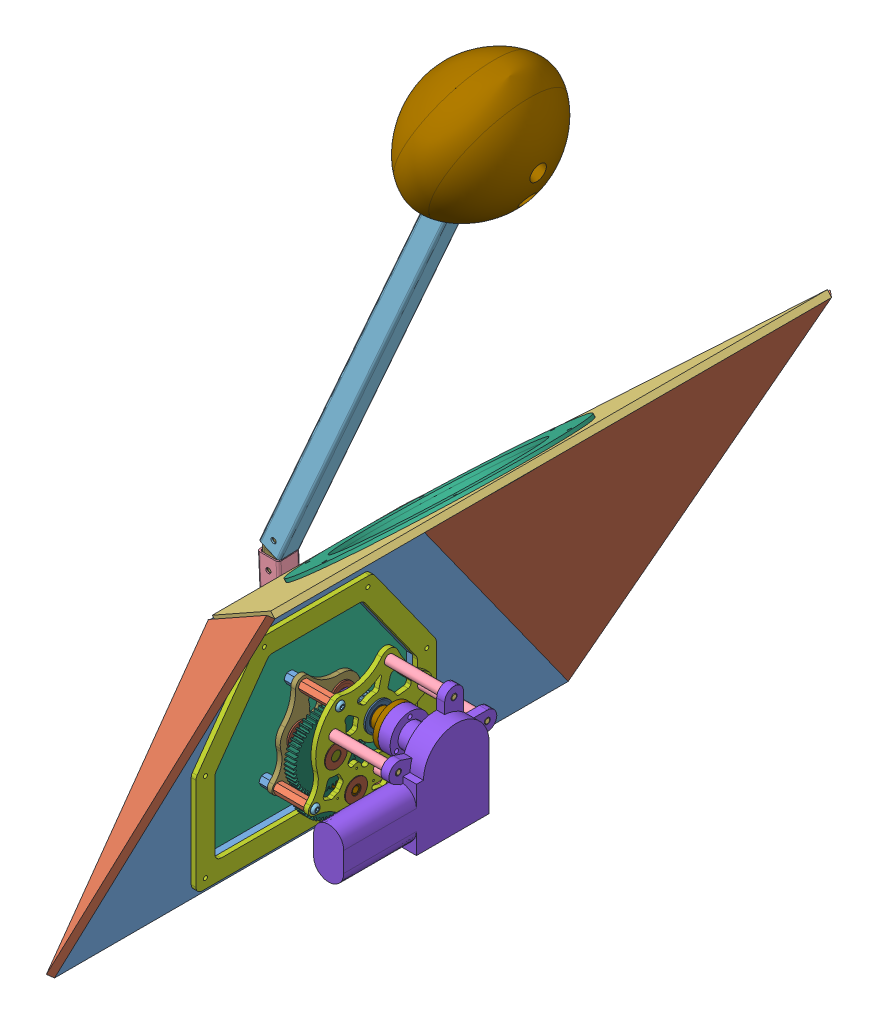
SolidWorks assembly Movable_Ballast, configuration Default. Lengths in mm.
Overall size (379.88 814.25 565.55).
62 component instances, 31 part files, 41 mates.
Components (placement in the parent):
- AngledBallast_DeckFront-1: AngledBallast_DeckFront [Default] at (17.6155 154.4397 181.7513) size (6.35 227.24 515.62)
- AngledBallast_DeckSides-1: AngledBallast_DeckSides [Default] at (23.9655 154.4397 439.5613) x (-0.750947 0.384211 0.537086) z (-0.47901 -0.876778 -0.042532) size (6.35 202.67 506.73)
- AngledBallast_DeckBack-1: AngledBallast_DeckBack [Default] at (262.5116 603.5077 -97.6487) x (0.666573 -0.74544 0) z (0 0 -1) size (6.35 325.69 558.8)
- AngledBallast_DeckSides-2: AngledBallast_DeckSides [Default] at (19.197 156.8794 -79.4692) x (0.750947 -0.384211 0.537086) z (-0.47901 -0.876778 0.042532) size (6.35 202.67 506.73)
- Ballast_Arm_Link1-1: Ballast_Arm_Link1 [Default] at (-1.1805 227.4494 182.4482) x (0 0.0439 -0.999036) z (0 0.999036 0.0439) size (21.59 21.59 161.93)
- Ballast_Arm_Link2-1: Ballast_Arm_Link2 [Default] at (212.1678 849.4759 209.7816) x (0 -0.0439 0.999036) z (-0.422618 -0.905434 -0.039787) size (21.97 21.97 501.65)
- 8inchHatch-2: 8inchHatch [Default] at (159.9893 499.0544 181.7513) x (0.74544 0.666573 0) z (0 0 1) size (248.92 12.7 248.92)
- LoweredMovableBallast-1: LoweredMovableBallast [AlternativeShaft] at (27.1405 211.5897 181.7513) x (0 -1 0) z (0 0 1) size (175.94 151.42 194.47)
  - Lowered_Ballast_Motor_Mount-1: Lowered_Ballast_Motor_Mount [Default] at (-131.0617 41.275 -47.2491) x (0 -1 0) z (-0.891007 0 0.45399) size (4.86 136.94 127.69)
  - Ballast_Motor_Mock-1: Ballast_Motor_Mock [Default] at (-52.6913 119.925 -55.3661) x (0 -1 0) z (0 0 1) size (58.5 115.03 167.12)
  - Ballast_Motor_Hub-1: Ballast_Motor_Hub [Default] at (-52.6913 61.425 -22.3661) x (-0.866025 0 -0.5) z (0 -1 0) size (40 40 17.78)
  - Hex_1_2in_Bearing_217-3875-STEP-20140818-1: Hex_1_2in_Bearing_217-3875-STEP-20140818 [Default] at (-52.6913 42.8625 -22.3661) x (-0.866025 0 -0.5) z (-0.5 0 0.866025) size (31.12 7.94 31.12)
  - 217-2733.20121205-1: 217-2733.20121205 [Default] at (-39.6731 34.925 20.2145) x (0 1 0) z (0.924225 0 0.381849) size (7.11 24.61 24.61)
  - 217-2733.20121205-2: 217-2733.20121205 [Default] at (0 34.925 0) x (0 1 0) z (-0.995143 0 0.098436) size (7.11 24.61 24.61)
  - Movable_Ballast_GearboxTopPlate-1: Movable_Ballast_GearboxTopPlate [Default] at (-131.0617 9.525 -47.2491) x (0 -1 0) z (-0.891007 0 0.45399) size (4.76 104.01 127.69)
  - 217-2733.20121205-3: 217-2733.20121205 [Default] at (-39.6731 6.35 20.2145) x (0 -1 0) z (0 0 1) size (7.11 24.61 24.61)
  - 217-2733.20121205-4: 217-2733.20121205 [Default] at (-52.6913 6.35 -22.3661) x (0 -1 0) z (0 0 1) size (7.11 24.61 24.61)
  - 217-2731.20121205-1: 217-2731.20121205 [Default] at (0 -1.5875 0) x (-0.381849 0 0.924225) z (-0.924225 0 -0.381849) size (31.12 7.94 31.12)
  - 217-3209-STEP-1: 217-3209-STEP [Default] at (-39.6731 16.0004 20.2145) x (0.901904 0 0.431937) z (0 1 0) size (25.77 25.98 12.65)
  - 217-3209-STEP-2: 217-3209-STEP [Default] at (-52.6913 29.895 -22.3661) x (-0.5 0 0.866025) z (0 -1 0) size (25.77 25.98 12.65)
  - 217-5473-STEP-1: 217-5473-STEP [Default] at (0 14.7304 0) x (0.887141 0 0.461499) z (0 -1 0) size (69.25 69.25 12.6)
  - 217-5473-STEP-2: 217-5473-STEP [Default] at (-39.6731 28.625 20.2145) x (-0.901904 0 -0.431937) z (0 -1 0) size (69.25 69.25 12.6)
  - MoveableBallast_IntermediateShaft-1: MoveableBallast_IntermediateShaft [Default] at (-39.6731 20.7645 20.2145) x (-0.82502 0 0.565103) z (0.565103 0 0.82502) size (12.7 41.27 14.66)
  - MoveableBallast_InputShaft-1: MoveableBallast_InputShaft [Default] at (-52.6913 61.425 -22.3661) x (0.5 0 0.866025) z (0.866025 0 -0.5) size (12.7 60.96 14.66)
  - MoveableBallast_OutputShaft-1: MoveableBallast_OutputShaft [AlternativeShaft] at (0 34.925 0) x (0.0439 0 0.999036) z (0.999036 0 -0.0439) size (12.7 72.77 14.66)
  - 91075A171_18-8 SS MALE-FEM THRDED HEX STANDOFF-5: 91075A171_18-8 SS MALE-FEM THRDED HEX STANDOFF [91075A171] at (-4.0577 0 41.0751) x (0 1 0) z (-0.999527 0 0.030764) size (19.59 11 9.53)
  - 91075A171_18-8 SS MALE-FEM THRDED HEX STANDOFF-6: 91075A171_18-8 SS MALE-FEM THRDED HEX STANDOFF [91075A171] at (-80.7194 0 15.875) x (0 1 0) z (0.485103 0 0.874457) size (19.59 11 9.53)
  - 91075A171_18-8 SS MALE-FEM THRDED HEX STANDOFF-3: 91075A171_18-8 SS MALE-FEM THRDED HEX STANDOFF [91075A171] at (19.05 0 -38.1) x (0 1 0) z (-0.636236 0 0.771494) size (19.59 11 9.53)
  - 91075A171_18-8 SS MALE-FEM THRDED HEX STANDOFF-4: 91075A171_18-8 SS MALE-FEM THRDED HEX STANDOFF [91075A171] at (-34.925 0 -38.1) x (0 1 0) z (0.444729 0 -0.895665) size (19.59 11 9.53)
  - 91780A304_ALUM FEM THRDED HEX STANDOFF-6: 91780A304_ALUM FEM THRDED HEX STANDOFF [91780A304] at (-4.0577 20.6375 41.0751) x (-0.985591 0 -0.169146) z (0 1 0) size (9.53 11 32.37)
  - 91780A304_ALUM FEM THRDED HEX STANDOFF-8: 91780A304_ALUM FEM THRDED HEX STANDOFF [91780A304] at (-34.925 20.6375 -38.1) x (1 0 0) z (0 -1 0) size (9.53 11 32.37)
  - 91780A304_ALUM FEM THRDED HEX STANDOFF-9: 91780A304_ALUM FEM THRDED HEX STANDOFF [91780A304] at (-80.7194 20.6375 15.875) x (1 0 0) z (0 1 0) size (9.53 11 32.37)
  - 91780A304_ALUM FEM THRDED HEX STANDOFF-10: 91780A304_ALUM FEM THRDED HEX STANDOFF [91780A304] at (19.05 20.6375 -38.1) x (0.996824 0 -0.079633) z (0 -1 0) size (9.53 11 32.37)
  - 92125A258_TYPE 18-8 SS FLAT-HEAD SOCKET CAP SCREW-1: 92125A258_TYPE 18-8 SS FLAT-HEAD SOCKET CAP SCREW [92125A258] at (-96.1913 36.5125 -33.6661) x (1 0 0) z (0 -1 0) size (12 12 70.91)
  - 92125A258_TYPE 18-8 SS FLAT-HEAD SOCKET CAP SCREW-2: 92125A258_TYPE 18-8 SS FLAT-HEAD SOCKET CAP SCREW [92125A258] at (-58.6913 36.5125 -66.9661) x (1 0 0) z (0 -1 0) size (12 12 70.91)
  - 92125A258_TYPE 18-8 SS FLAT-HEAD SOCKET CAP SCREW-3: 92125A258_TYPE 18-8 SS FLAT-HEAD SOCKET CAP SCREW [92125A258] at (-58.6913 36.5125 22.2339) x (-0.551717 0 0.834031) z (0 -1 0) size (12 12 70.91)
  - 92125A258_TYPE 18-8 SS FLAT-HEAD SOCKET CAP SCREW-4: 92125A258_TYPE 18-8 SS FLAT-HEAD SOCKET CAP SCREW [92125A258] at (-7.6913 36.5125 -22.3661) x (1 0 0) z (0 -1 0) size (12 12 70.91)
  - MoveableBallast_MotorSpacer_9038K24_Stock-1: MoveableBallast_MotorSpacer_9038K24_Stock [Default] at (-58.6913 41.275 -66.9661) x (-0.794722 0 -0.606973) z (0.606973 0 -0.794722) size (9.53 57.15 9.53)
  - MoveableBallast_MotorSpacer_9038K24_Stock-2: MoveableBallast_MotorSpacer_9038K24_Stock [Default] at (-7.6913 41.275 -22.3661) x (0.166881 0 0.985977) z (-0.985977 0 0.166881) size (9.53 57.15 9.53)
  - MoveableBallast_MotorSpacer_9038K24_Stock-3: MoveableBallast_MotorSpacer_9038K24_Stock [Default] at (-96.1913 41.275 -33.6661) x (0.202474 0 0.979288) z (-0.979288 0 0.202474) size (9.53 57.15 9.53)
  - MoveableBallast_MotorSpacer_9038K24_Stock-4: MoveableBallast_MotorSpacer_9038K24_Stock [Default] at (-58.6913 41.275 22.2339) x (0.889131 0 0.457652) z (-0.457652 0 0.889131) size (9.53 57.15 9.53)
  - 92949A263_18-8 SS BUTTON-HEAD SOCKET CAP SCREW-1: 92949A263_18-8 SS BUTTON-HEAD SOCKET CAP SCREW [92949A263] at (-80.7194 43.8404 15.875) x (0.459564 0 -0.888145) z (0 1 0) size (9.17 9.17 12.55)
  - 92949A263_18-8 SS BUTTON-HEAD SOCKET CAP SCREW-2: 92949A263_18-8 SS BUTTON-HEAD SOCKET CAP SCREW [92949A263] at (-4.0577 43.8404 41.0751) x (1 0 0) z (0 1 0) size (9.17 9.17 12.55)
  - 92949A263_18-8 SS BUTTON-HEAD SOCKET CAP SCREW-3: 92949A263_18-8 SS BUTTON-HEAD SOCKET CAP SCREW [92949A263] at (19.05 43.8404 -38.1) x (1 0 0) z (0 1 0) size (9.17 9.17 12.55)
  - 92949A263_18-8 SS BUTTON-HEAD SOCKET CAP SCREW-4: 92949A263_18-8 SS BUTTON-HEAD SOCKET CAP SCREW [92949A263] at (-34.925 43.8404 -38.1) x (1 0 0) z (0 1 0) size (9.17 9.17 12.55)
- LoweredBallast_Deck_Mount-1: LoweredBallast_Deck_Mount [Default] at (23.9655 154.4397 181.7513) x (-1 0 0) z (0 0 -1) size (11.43 227.24 515.62)
- LoweredBallast_DeckMount_ClampPlate-1: LoweredBallast_DeckMount_ClampPlate [Default] at (17.6155 154.4397 181.7513) size (11.11 227.24 515.62)
- 92949A263_18-8 SS BUTTON-HEAD SOCKET CAP SCREW-1: 92949A263_18-8 SS BUTTON-HEAD SOCKET CAP SCREW [92949A263] at (9.9701 246.5147 143.6513) x (0 -0.883456 -0.468514) z (-1 0 0) size (9.17 9.17 12.55)
- 92949A263_18-8 SS BUTTON-HEAD SOCKET CAP SCREW-2: 92949A263_18-8 SS BUTTON-HEAD SOCKET CAP SCREW [92949A263] at (9.9701 192.5397 143.6513) x (0 0.924225 0.381849) z (-1 0 0) size (9.17 9.17 12.55)
- 92949A263_18-8 SS BUTTON-HEAD SOCKET CAP SCREW-3: 92949A263_18-8 SS BUTTON-HEAD SOCKET CAP SCREW [92949A263] at (9.9701 215.6473 222.8264) x (0 0.91527 -0.402841) z (-1 0 0) size (9.17 9.17 12.55)
- 92949A263_18-8 SS BUTTON-HEAD SOCKET CAP SCREW-4: 92949A263_18-8 SS BUTTON-HEAD SOCKET CAP SCREW [92949A263] at (9.9701 292.3091 197.6263) x (0 0 1) z (-1 0 0) size (9.17 9.17 12.55)
- 13125K830_CHEMICAL-RESISTANT SHAFT SEAL-1: 13125K830_CHEMICAL-RESISTANT SHAFT SEAL [13125K83] at (14.7199 211.5897 181.7513) x (1 0 0) z (0 -0.168673 0.985672) size (4.37 19.67 19.67)
- Ballast_Weight_Assembly-1: Ballast_Weight_Assembly [Default] at (222.9023 872.474 210.7922) x (-0.422618 -0.905434 -0.039787) z (0 0.0439 -0.999036) size (152.07 114.4 139.83)
  - Ballast_Weight-1: Ballast_Weight [Default] at origin size (152.07 114.4 139.83)
  - Ballast_Weight-2: Ballast_Weight [Ballast Weight Outside] at origin size (144.63 51.5 137.25)
  - Ballast_Weight-3: Ballast_Weight [Ballast Weight Outside] x (1 0 0) z (0 0 -1) size (144.63 51.5 137.25)
  - 92196A554_18-8 STAINLESS STEEL SOCKET HEAD CAP SCREW-1: 92196A554_18-8 STAINLESS STEEL SOCKET HEAD CAP SCREW [92196A554] at (12.7 41.275 0) x (1 0 0) z (0 1 0) size (9.53 9.53 83.33)
  - 92196A554_18-8 STAINLESS STEEL SOCKET HEAD CAP SCREW-2: 92196A554_18-8 STAINLESS STEEL SOCKET HEAD CAP SCREW [92196A554] at (-20.32 41.275 0) x (0.947644 0 -0.319328) z (0 1 0) size (9.53 9.53 83.33)
  - 92673A113_ASTM F594 TYPE 18-8 STAINLESS STEEL HEX NUT-2: 92673A113_ASTM F594 TYPE 18-8 STAINLESS STEEL HEX NUT [92673A113] at (-20.32 37.7031 0) x (1 0 0) z (0 1 0) size (11.11 12.83 7.14)
  - 92673A113_ASTM F594 TYPE 18-8 STAINLESS STEEL HEX NUT-3: 92673A113_ASTM F594 TYPE 18-8 STAINLESS STEEL HEX NUT [92673A113] at (12.7 37.7031 0) x (0.939231 0 0.343287) z (0 1 0) size (11.11 12.83 7.14)
- Ballast_Arm_Joint-1: Ballast_Arm_Joint [Default<As Machined>] at (-1.1805 392.3902 189.6961) x (0.21644 0.975355 0.04286) z (0.976296 -0.216231 -0.009502) size (59.92 19.06 25.24)
- AlternativeMBCoupler-1: AlternativeMBCoupler [Default] at (-1.1805 252.8249 183.5633) x (0 -0.0439 0.999036) z (0 -0.999036 -0.0439) size (19.05 19.05 50.8)
Mates (geometry in assembly coordinates):
- Coincident10: coincident aligned: line of AngledBallast_DeckFront-1 through (23.9655 381.681 277.0013) axis (0 -0.813319 0.581818); line of AngledBallast_DeckSides-1 through (23.9655 381.681 277.0013) axis (0 -0.813319 0.581818)
- Coincident11: coincident aligned: line of AngledBallast_DeckBack-1 through (266.7443 598.7742 461.1513) axis (-0.648895 -0.580243 -0.492193); line of AngledBallast_DeckSides-1 through (266.6944 598.7295 461.1134) axis (-0.648895 -0.580243 -0.492193)
- Coincident12: coincident anti-aligned: line of AngledBallast_DeckBack-1 through (23.9655 381.681 86.5013) axis (0.648895 0.580243 -0.492193); line of AngledBallast_DeckSides-2 through (266.6944 598.7295 -97.6108) axis (-0.648895 -0.580243 0.492193)
- Coincident13: coincident anti-aligned: line of AngledBallast_DeckFront-1 through (23.9655 154.4397 -76.0587) axis (0 0.813319 0.581818); line of AngledBallast_DeckSides-2 through (23.9655 381.681 86.5013) axis (0 -0.813319 -0.581818)
- Coincident30: coincident anti-aligned: line of AngledBallast_DeckFront-1 through (23.9655 381.681 86.5013) axis (0 0 1); line of AngledBallast_DeckBack-1 through (23.9655 381.681 277.0013) axis (0 0 -1)
- Concentric4: concentric aligned: circle of AngledBallast_DeckBack-1; circle of 8inchHatch-2
- Coincident58: coincident anti-aligned: plane of AngledBallast_DeckBack-1 through (262.5116 603.5077 -97.6487) normal (-0.666573 0.74544 0); plane of 8inchHatch-2 through (153.6401 506.1547 89.0413) normal (0.666573 -0.74544 0)
- Parallel2: parallel aligned: line of AngledBallast_DeckFront-1 through (17.6155 179.8397 283.3513) axis (0 0 -1); line of LoweredMovableBallast-1/Ballast_Motor_Mock-1 through (125.5655 202.281 199.3852) axis (0 0 -1)
- Concentric10: concentric anti-aligned: cylinder of LoweredMovableBallast-1/MoveableBallast_OutputShaft-1 through (-4.3555 211.5897 181.7513) axis (1 0 0) radius 6.35; cylinder of LoweredBallast_Deck_Mount-1 through (23.9655 211.5897 181.7513) axis (-1 0 0) radius 8.7312
- Concentric11: concentric aligned: cylinder of AngledBallast_DeckFront-1 through (23.9655 259.0958 292.8763) axis (1 0 0) radius 2.5527; cylinder of LoweredBallast_DeckMount_ClampPlate-1 through (28.728 259.0958 292.8763) axis (1 0 0) radius 2.0193
- Concentric12: concentric aligned: cylinder of AngledBallast_DeckFront-1 through (23.9655 259.0958 70.6263) axis (1 0 0) radius 2.5527; cylinder of LoweredBallast_Deck_Mount-1 through (12.5355 259.0958 70.6263) axis (1 0 0) radius 2.5527
- Concentric13: concentric aligned: cylinder of AngledBallast_DeckFront-1 through (23.9655 170.3147 70.6263) axis (1 0 0) radius 2.5527; cylinder of LoweredBallast_Deck_Mount-1 through (12.5355 170.3147 70.6263) axis (1 0 0) radius 2.5527
- Coincident78: coincident anti-aligned: plane of AngledBallast_DeckFront-1 through (17.6155 154.4397 181.7513) normal (-1 0 0); plane of LoweredBallast_Deck_Mount-1 through (17.6155 154.4397 181.7513) normal (1 0 0)
- Coincident79: coincident aligned: plane of LoweredBallast_Deck_Mount-1 through (12.5355 154.4397 181.7513) normal (-1 0 0); circle of 92949A263_18-8 SS BUTTON-HEAD SOCKET CAP SCREW-2
- Concentric14: concentric aligned: circle of LoweredBallast_Deck_Mount-1; circle of 92949A263_18-8 SS BUTTON-HEAD SOCKET CAP SCREW-2
- Concentric15: concentric aligned: cylinder of LoweredBallast_Deck_Mount-1 through (12.5355 246.5147 143.6513) axis (-1 0 0) radius 2.4892; circle of 92949A263_18-8 SS BUTTON-HEAD SOCKET CAP SCREW-1
- Coincident80: coincident anti-aligned: plane of LoweredBallast_Deck_Mount-1 through (12.5355 154.4397 181.7513) normal (-1 0 0); plane of 92949A263_18-8 SS BUTTON-HEAD SOCKET CAP SCREW-1 through (12.5355 248.6627 139.6009) normal (1 0 0)
- Coincident81: coincident anti-aligned: plane of LoweredBallast_Deck_Mount-1 through (12.5355 154.4397 181.7513) normal (-1 0 0); plane of 92949A263_18-8 SS BUTTON-HEAD SOCKET CAP SCREW-3 through (12.5355 217.4943 227.0226) normal (1 0 0)
- Concentric16: concentric aligned: circle of LoweredBallast_Deck_Mount-1; circle of 92949A263_18-8 SS BUTTON-HEAD SOCKET CAP SCREW-3
- Coincident82: coincident aligned: plane of LoweredBallast_Deck_Mount-1 through (12.5355 154.4397 181.7513) normal (-1 0 0); circle of 92949A263_18-8 SS BUTTON-HEAD SOCKET CAP SCREW-4
- Concentric17: concentric aligned: cylinder of LoweredBallast_Deck_Mount-1 through (12.5355 292.3091 197.6263) axis (-1 0 0) radius 2.4892; circle of 92949A263_18-8 SS BUTTON-HEAD SOCKET CAP SCREW-4
- Concentric18: concentric anti-aligned: circle of LoweredBallast_Deck_Mount-1; circle of 13125K830_CHEMICAL-RESISTANT SHAFT SEAL-1
- Coincident84: coincident aligned: plane of LoweredBallast_Deck_Mount-1 through (12.5355 154.4397 181.7513) normal (-1 0 0); plane of 13125K830_CHEMICAL-RESISTANT SHAFT SEAL-1 through (12.5355 220.4172 183.2619) normal (-1 0 0)
- Concentric19: concentric aligned: cylinder of AngledBallast_DeckFront-1 through (23.9655 170.3147 292.8763) axis (1 0 0) radius 2.5527; cylinder of LoweredBallast_DeckMount_ClampPlate-1 through (28.728 170.3147 292.8763) axis (1 0 0) radius 2.0193
- Coincident85: coincident anti-aligned: plane of AngledBallast_DeckFront-1 through (23.9655 154.4397 181.7513) normal (1 0 0); plane of LoweredBallast_DeckMount_ClampPlate-1 through (23.9655 154.4397 181.7513) normal (-1 0 0)
- Coincident88: coincident anti-aligned: plane of LoweredMovableBallast-1/91075A171_18-8 SS MALE-FEM THRDED HEX STANDOFF-5 through (17.6155 215.8165 217.3297) normal (-1 0 0); plane of LoweredBallast_Deck_Mount-1 through (17.6155 154.4397 181.7513) normal (1 0 0)
- Coincident91: coincident anti-aligned: plane of Ballast_Arm_Link2-1 through (8.7939 390.8252 199.1616) normal (0 0.0439 -0.999036); plane of Ballast_Arm_Joint-1 through (-4.0718 363.2613 197.9503) normal (0 -0.0439 0.999036)
- Coincident92: coincident anti-aligned: plane of Ballast_Arm_Link2-1 through (-8.4712 398.8684 199.515) normal (0.906308 -0.422211 -0.018553); plane of Ballast_Arm_Joint-1 through (-21.3369 372.1407 179.2721) normal (-0.906308 0.422211 0.018553)
- Coincident93: coincident anti-aligned: plane of Ballast_Arm_Link1-1 through (-10.7055 389.6364 180.0409) normal (1 0 0); plane of Ballast_Arm_Joint-1 through (-10.7055 420.0499 181.3774) normal (-1 0 0)
- Coincident94: coincident anti-aligned: plane of Ballast_Arm_Link1-1 through (8.3445 388.8001 199.0726) normal (0 0.0439 -0.999036); plane of Ballast_Arm_Joint-1 through (8.3445 419.2136 200.409) normal (0 -0.0439 0.999036)
- Coincident96: coincident anti-aligned: plane of Ballast_Arm_Link2-1 through (10.1176 391.109 178.6437) normal (0 0.0439 -0.999036); plane of Ballast_Weight_Assembly-1/Ballast_Weight-1 through (222.124 845.32 198.6029) normal (0 -0.0439 0.999036)
- Coincident97: coincident anti-aligned: plane of Ballast_Arm_Link2-1 through (-9.7949 399.4209 201.0012) normal (-0.906308 0.422211 0.018553); plane of Ballast_Weight_Assembly-1/Ballast_Weight-1 through (202.2115 854.5964 199.0105) normal (0.906308 -0.422211 -0.018553)
- Coincident98: coincident anti-aligned: plane of Ballast_Arm_Link2-1 through (212.1678 849.4759 209.7816) normal (0.422618 0.905434 0.039787); plane of Ballast_Weight_Assembly-1/Ballast_Weight-1 through (212.1678 849.4759 209.7816) normal (-0.422618 -0.905434 -0.039787)
- Coincident99: coincident anti-aligned: plane of LoweredMovableBallast-1/MoveableBallast_OutputShaft-1 through (8.3445 211.4154 185.7162) normal (0 -0.0439 0.999036); plane of AlternativeMBCoupler-1 through (-4.3555 208.2435 185.5769) normal (0 0.0439 -0.999036)
- Concentric25: concentric anti-aligned: cylinder of LoweredMovableBallast-1/MoveableBallast_OutputShaft-1 through (-4.3555 211.5897 181.7513) axis (-1 0 0) radius 1.7272; cylinder of AlternativeMBCoupler-1 through (-4.3555 211.5897 181.7513) axis (1 0 0) radius 2.2479
- Coincident100: coincident anti-aligned: plane of LoweredMovableBallast-1/MoveableBallast_OutputShaft-1 through (-4.3555 211.5897 181.7513) normal (-1 0 0); plane of AlternativeMBCoupler-1 through (-4.3555 208.4526 180.8189) normal (1 0 0)
- Coincident101: coincident anti-aligned: plane of Ballast_Arm_Link1-1 through (8.3445 388.8001 199.0726) normal (0 0.0439 -0.999036); plane of AlternativeMBCoupler-1 through (-10.7055 201.6557 190.849) normal (0 -0.0439 0.999036)
- Concentric26: concentric aligned: cylinder of Ballast_Arm_Link1-1 through (-11.9755 240.1371 183.0058) axis (-1 0 0) radius 2.5527; cylinder of AlternativeMBCoupler-1 through (-10.7055 240.1371 183.0058) axis (-1 0 0) radius 2.0193
- Coincident102: coincident anti-aligned: plane of Ballast_Arm_Link1-1 through (-10.7055 389.6364 180.0409) normal (1 0 0); plane of AlternativeMBCoupler-1 through (-10.7055 202.492 171.8173) normal (-1 0 0)
- Concentric27: concentric aligned: cylinder of Ballast_Arm_Link1-1 through (-1.1805 376.0566 199.7838) axis (0 -0.0439 0.999036) radius 2.5527; cylinder of Ballast_Arm_Joint-1 through (-1.1805 376.1124 198.515) axis (0 -0.0439 0.999036) radius 2.0193
- Concentric28: concentric aligned: cylinder of Ballast_Arm_Link2-1 through (5.5286 406.2817 201.3027) axis (0 -0.0439 0.999036) radius 2.5527; cylinder of Ballast_Arm_Joint-1 through (5.5286 406.3458 199.8436) axis (0 -0.0439 0.999036) radius 2.0193
